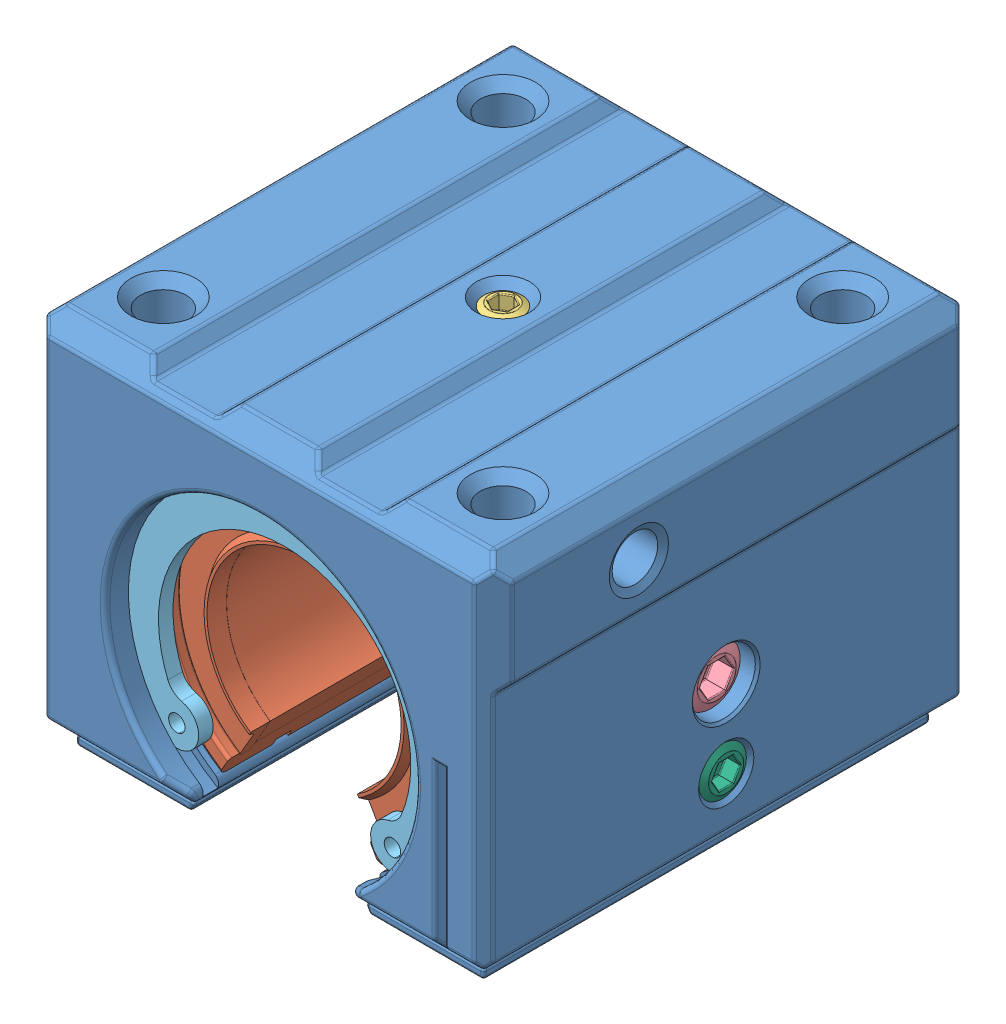
SolidWorks assembly SBR20UU, configuration По умолчанию. Lengths in mm.
Overall size (48 39 50).
7 component instances, 6 part files, 15 mates.
Components (placement in the parent):
- Корпус SBR20UU-1: Корпус SBR20UU [По умолчанию] at origin size (48 39 50)
- Подшипник LM20UUOP-1: Подшипник LM20UUOP [По умолчанию] at origin size (32 29.64 42.03)
- Стопорный винт М4х6-1: Стопорный винт М4х6 [По умолчанию] at (0 22.5218 0) x (0 -1 0) z (0 0 1) size (6.5 4 4)
- Стопорный винт М6х6-1: Стопорный винт М6х6 [По умолчанию] at (22.0227 0 0) x (-1 0 0) z (0 0 1) size (6 6 6)
- Стопорное кольцо-1: Стопорное кольцо [По умолчанию] at (0 0 22.5) x (-1 0 0) z (0 0 1) size (33.5 28.32 1.5)
- Стопорное кольцо-2: Стопорное кольцо [По умолчанию] at (0 0 -21) x (-1 0 0) z (0 0 1) size (33.5 28.32 1.5)
- Стопорный винт М5х5-1: Стопорный винт М5х5 [По умолчанию] at (23 -8 0) x (-1 0 0) z (0 0 1) size (5 5 5)
Mates (geometry in assembly coordinates):
- Концентричный1: concentric anti-aligned: cylinder of Корпус SBR20UU-1 through (0 0 25) axis (0 0 -1) radius 16; cylinder of Подшипник LM20UUOP-1 through (0 0 43.3432) axis (0 0 1) radius 16
- Совпадение1: coincident aligned: plane of Корпус SBR20UU-1 through (0 0 -21) normal (0 0 -1); plane of Подшипник LM20UUOP-1 through (0 0 -21) normal (0 0 -1)
- Концентричный2: concentric aligned: cylinder of Корпус SBR20UU-1 through (0 -16 0) axis (0 1 0) radius 1.75; cylinder of Стопорный винт М4х6-1 through (0 16.0218 0) axis (0 1 0) radius 2
- Концентричный3: concentric aligned: cylinder of Корпус SBR20UU-1 through (13 0 0) axis (1 0 0) radius 2.5; cylinder of Стопорный винт М6х6-1 through (16.0227 0 0) axis (1 0 0) radius 3
- Концентричный4: concentric aligned: circle of Корпус SBR20UU-1; circle of Стопорное кольцо-1
- Совпадение2: coincident anti-aligned: plane of Корпус SBR20UU-1 through (0 0 21) normal (0 0 1); plane of Стопорное кольцо-1 through (0 0 21) normal (0 0 -1)
- Концентричный5: concentric aligned: circle of Корпус SBR20UU-1; circle of Стопорное кольцо-2
- Совпадение3: coincident anti-aligned: plane of Корпус SBR20UU-1 through (0 0 -21) normal (0 0 -1); plane of Стопорное кольцо-2 through (0 0 -21) normal (0 0 1)
- Параллельность1: parallel aligned: plane of Корпус SBR20UU-1 through (0 23 25) normal (0 1 0); plane of Стопорный винт М6х6-1 through (20.0227 -1.5 0.866) normal (0 1 0)
- Параллельность2: parallel aligned: plane of Корпус SBR20UU-1 through (24 0 25) normal (1 0 0); plane of Стопорный винт М4х6-1 through (-1 21.0218 -0.5774) normal (1 0 0)
- Параллельность3: parallel aligned: plane of Корпус SBR20UU-1 through (0 23 25) normal (0 1 0); plane of Стопорный винт М5х5-1 through (21.5 -9.25 0.7217) normal (0 1 0)
- Совпадение4: coincident anti-aligned: plane of Корпус SBR20UU-1 through (18 -15 -25) normal (1 0 0); plane of Стопорный винт М5х5-1 through (18 -10.5 0) normal (-1 0 0)
- Концентричный6: concentric anti-aligned: cylinder of Корпус SBR20UU-1 through (29.0811 -8 0) axis (-1 0 0) radius 2.15; cylinder of Стопорный винт М5х5-1 through (18 -8 0) axis (1 0 0) radius 2.5
- Концентричный7: concentric anti-aligned: cylinder of Подшипник LM20UUOP-1 through (0 0 43.3432) axis (0 0 1) radius 10; cylinder of ? through (0 0 211.5511) axis (0 0 -1) radius 10
- Параллельность4: parallel aligned: plane of Корпус SBR20UU-1 through (0 23 25) normal (0 1 0); plane of ? through (0 -22 211.5511) normal (0 1 0)
